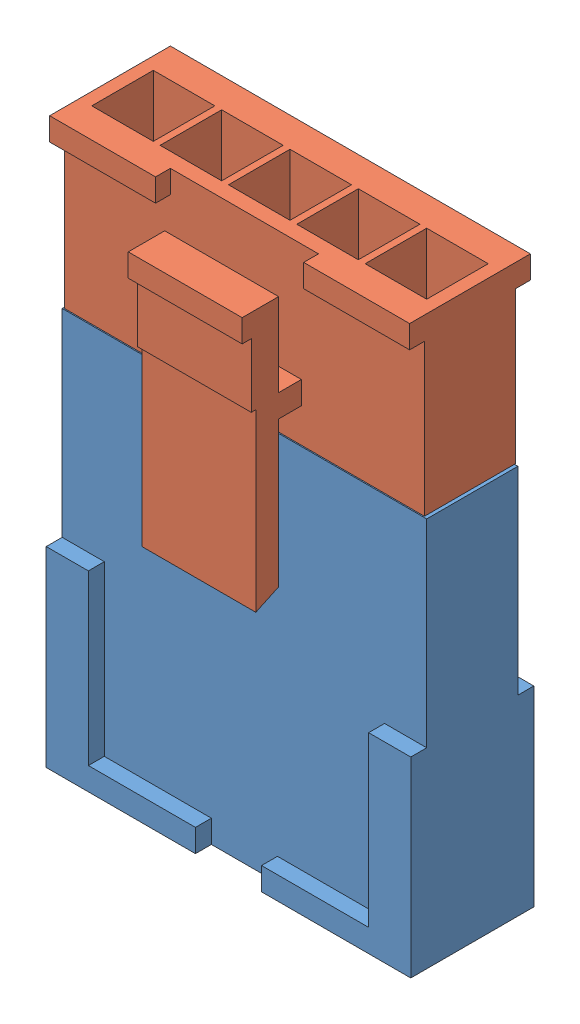
SolidWorks assembly Assem5, configuration Default. Lengths in mm.
Overall size (16 24.8 7.3).
2 component instances, 2 part files, 3 mates.
Components (placement in the parent):
- balance-plug-1: balance-plug [Default] at origin size (16 17.1 5.7)
- balance-receptacle-1: balance-receptacle [Default] at (0 24.8 0) x (-1 0 0) z (0 0 1) size (15.8 14 7.25)
Mates (geometry in assembly coordinates):
- Width2: width: plane of balance-plug-1 through (-8 17.1 2) normal (0 0 1); plane of balance-plug-1 through (-8 17.1 -2) normal (0 0 -1); plane of balance-receptacle-1 through (7.9 18.4379 2) normal (0 0 1); plane of balance-receptacle-1 through (7.9 18.4379 -2) normal (0 0 -1)
- Width3: width: plane of balance-plug-1 through (8 17.1 -2) normal (1 0 0); plane of balance-plug-1 through (-8 17.1 -2) normal (-1 0 0); plane of balance-receptacle-1 through (7.9 18.4379 -2) normal (1 0 0); plane of balance-receptacle-1 through (-7.9 18.4379 -2) normal (-1 0 0)
- Distance1: distance = 0.05 mm: plane of balance-receptacle-1 through (0 17.15 0) normal (0 -1 0); plane of balance-plug-1 through (0 17.1 0) normal (0 1 0)
